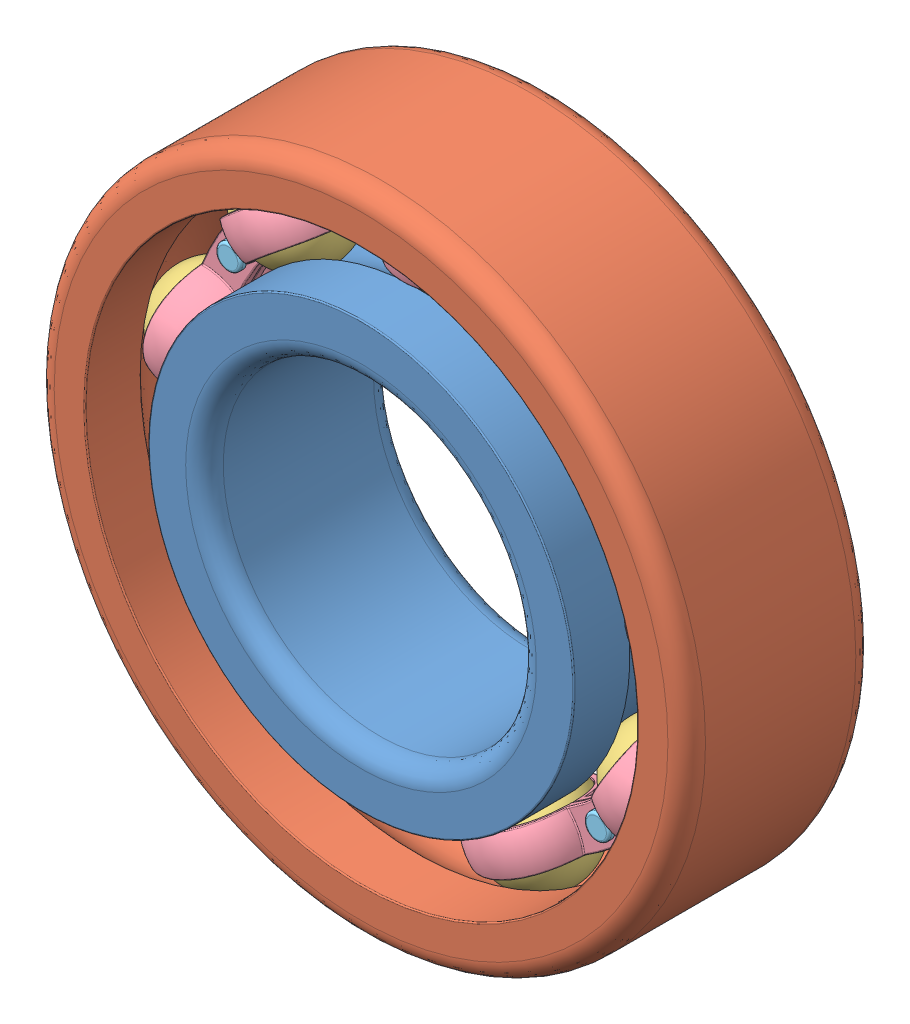
SolidWorks assembly 6205, configuration Default. Lengths in mm.
Overall size (66.56 66.47 15).
23 component instances, 5 part files, 0 mates.
Components (placement in the parent):
- 6205.stp-1: 6205.stp [Default] at origin size (66.56 66.47 15)
  - Inner Race.stp-1: Inner Race.stp [Default] at origin size (34 34 15)
  - Outer Race.stp-1: Outer Race.stp [Default] at origin size (52 52 15)
  - Ball.stp-1: Ball.stp [Default] at (0 19.55 0) size (7.94 7.94 7.94)
  - Ball.stp-2: Ball.stp [Default] at (12.5665 14.9762 0) x (0.766044 -0.642788 0) z (0 0 1) size (7.94 7.94 7.94)
  - Ball.stp-3: Ball.stp [Default] at (19.253 3.3948 0) x (0.173648 -0.984808 0) z (0 0 1) size (7.94 7.94 7.94)
  - Ball.stp-4: Ball.stp [Default] at (16.9308 -9.775 0) x (-0.5 -0.866025 0) z (0 0 1) size (7.94 7.94 7.94)
  - Ball.stp-5: Ball.stp [Default] at (6.6865 -18.371 0) x (-0.939693 -0.34202 0) z (0 0 1) size (7.94 7.94 7.94)
  - Ball.stp-6: Ball.stp [Default] at (-6.6865 -18.371 0) x (-0.939693 0.34202 0) z (0 0 1) size (7.94 7.94 7.94)
  - Ball.stp-7: Ball.stp [Default] at (-16.9308 -9.775 0) x (-0.5 0.866025 0) z (0 0 1) size (7.94 7.94 7.94)
  - Ball.stp-8: Ball.stp [Default] at (-19.253 3.3948 0) x (0.173648 0.984808 0) z (0 0 1) size (7.94 7.94 7.94)
  - Ball.stp-9: Ball.stp [Default] at (-12.5665 14.9762 0) x (0.766044 0.642788 0) z (0 0 1) size (7.94 7.94 7.94)
  - Cage.stp-1: Cage.stp [Default] x (0.766044 -0.642788 0) z (0 0 1) size (47.54 46.88 4.69)
  - Cage.stp-2: Cage.stp [Default] x (-0.766044 0.642788 0) z (0 0 -1) size (47.54 46.88 4.69)
  - Rivit.stp-1: Rivit.stp [Default] at (-6.6694 18.324 0) x (0 -1 0) z (1 0 0) size (2 2.5 2)
  - Rivit.stp-2: Rivit.stp [Default] at (6.6694 18.324 0) x (-0.642788 -0.766044 0) z (0.766044 -0.642788 0) size (2 2.5 2)
  - Rivit.stp-3: Rivit.stp [Default] at (16.8875 9.75 0) x (-0.984808 -0.173648 0) z (0.173648 -0.984808 0) size (2 2.5 2)
  - Rivit.stp-4: Rivit.stp [Default] at (19.2038 -3.3861 0) x (-0.866025 0.5 0) z (-0.5 -0.866025 0) size (2 2.5 2)
  - Rivit.stp-5: Rivit.stp [Default] at (12.5344 -14.9379 0) x (-0.34202 0.939693 0) z (-0.939693 -0.34202 0) size (2 2.5 2)
  - Rivit.stp-6: Rivit.stp [Default] at (0 -19.5 0) x (0.34202 0.939693 0) z (-0.939693 0.34202 0) size (2 2.5 2)
  - Rivit.stp-7: Rivit.stp [Default] at (-12.5344 -14.9379 0) x (0.866025 0.5 0) z (-0.5 0.866025 0) size (2 2.5 2)
  - Rivit.stp-8: Rivit.stp [Default] at (-19.2038 -3.3861 0) x (0.984808 -0.173648 0) z (0.173648 0.984808 0) size (2 2.5 2)
  - Rivit.stp-9: Rivit.stp [Default] at (-16.8875 9.75 0) x (0.642788 -0.766044 0) z (0.766044 0.642788 0) size (2 2.5 2)
